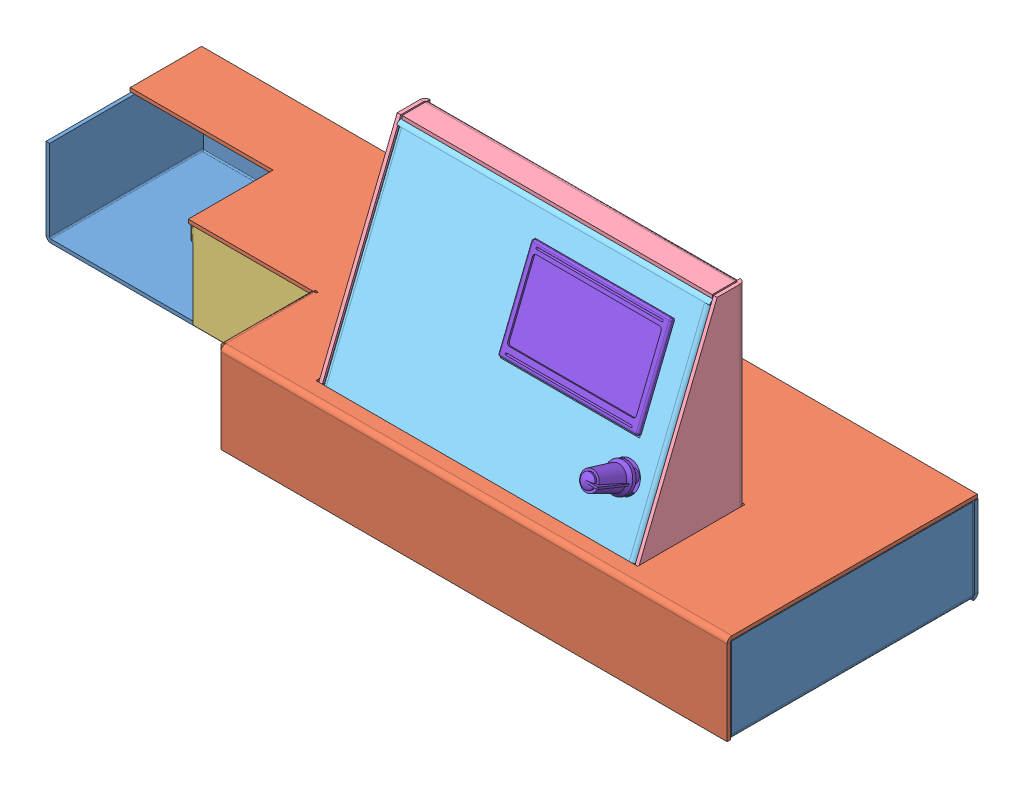
SolidWorks assembly case electronica, configuration Predeterminado. Lengths in mm.
Overall size (434 163.08 144.53).
15 component instances, 11 part files, 32 mates.
Components (placement in the parent):
- base case electronica-1: base case electronica [Predeterminado] at (-56.5036 -131.1225 434) size (434 48 138)
- Copia de Pieza2-1: Copia de Pieza2 [Predeterminado] at (0 0.5 0.4) size (434 50 140)
- Lateral case superior-1: Lateral case superior [Predeterminado] at (-0.5798 -10.8135 0.4) size (146 48 60)
- case panel base-1: case panel base [Predeterminado] at (10.9964 -29.5225 437.4) size (195 112.1 68)
- case panel frontal-1: case panel frontal [Predeterminado] at (10.9964 -30.4772 474.3319) x (1 0 0) z (0 0.374607 0.927184) size (175 123.88 18.04)
- bisagra conjunto-1: bisagra conjunto [Predeterminado] at (-193.3933 -102.5076 359.5703) size (40 28.4 28.4) (flexible)
  - bisagra 01-1: bisagra 01 [Predeterminado] at (-38.1103 2.1851 8.1797) size (40 28.4 3)
  - bisagra 02-1: bisagra 02 [Predeterminado] at (-38.1103 17.1351 23.1297) x (-1 0 0) z (0 -1 0) size (40 28.4 3)
- bisagra conjunto-2: bisagra conjunto [Predeterminado] at (156.6067 -102.5076 359.5703) size (40 28.4 28.4) (flexible)
  - bisagra 01-1: bisagra 01 [Predeterminado] at (-38.1103 2.1851 8.1797) size (40 28.4 3)
  - bisagra 02-1: bisagra 02 [Predeterminado] at (-38.1103 17.1351 23.1297) x (-1 0 0) z (0 -1 0) size (40 28.4 3)
- Display Controlador LCD Ramps 1.4-1: Display Controlador LCD Ramps 1.4 [Predeterminado] at (44.4964 -26.4399 459.5426) x (1 0 0) z (0 0.374607 0.927184) size (93 87.2 45.8)
- Arduino MEGA 2560 R3-1: Arduino MEGA 2560 R3 [Predeterminado] at (-34.9425 -75.8165 443.9) x (0 -1 0) z (-1 0 0) size (53.34 14.5 108.1)
- Shield Ramps 1.4-1: Shield Ramps 1.4 [Predeterminado] at (-35.3584 -79.6225 456.5471) x (0 -1 0) z (-1 0 0) size (61.76 37.63 106.38)
- Pieza6^case electronica-1: Pieza6^case electronica [Predeterminado] at (-43.3712 -108.7959 -211.9527) size (153.85 61.76 5) (virtual)
Mates (geometry in assembly coordinates):
- Coincidente1: coincident: plane of assembly; plane of assembly; plane of Copia de Pieza2-1 through (100.4964 -92.6225 495.4) normal (-1 0 0); plane of case panel base-1 through (100.4964 -29.5225 437.4) normal (1 0 0)
- Coincidente2: coincident: plane of assembly; plane of assembly; plane of Copia de Pieza2-1 through (-79.5036 -92.6225 435.4) normal (0 0 1); plane of case panel base-1 through (10.9964 -29.5225 435.4) normal (0 0 -1)
- Coincidente3: coincident: plane of assembly; plane of assembly; plane of Copia de Pieza2-1 through (0 -84.6225 0.4) normal (0 -1 0); plane of case panel base-1 through (10.9964 -84.6225 437.4) normal (0 1 0)
- Coincidente4: coincident: plane of assembly; plane of assembly; plane of case panel base-1 through (10.9964 23.4775 437.4) normal (0 -1 0); plane of case panel frontal-1 through (10.9964 23.4775 475.14) normal (0 1 0)
- Coincidente5: coincident: plane of assembly; plane of assembly; plane of case panel base-1 through (-76.5036 -29.5225 437.4) normal (1 0 0); plane of case panel frontal-1 through (-76.5036 -30.4772 474.3319) normal (-1 0 0)
- Coincidente6: coincident: line of assembly; plane of assembly; line of Copia de Pieza2-1 through (-79.5036 -82.6225 495.4) axis (1 0 0); plane of case panel frontal-1 through (10.9964 -30.4772 474.3319) normal (0 0.374607 0.927184)
- Coincidente11: coincident: plane of assembly; plane of assembly; plane of Copia de Pieza2-1 through (-273.5036 -82.6225 452.9) normal (0 0 1); plane of Lateral case superior-1 through (-0.5798 -10.8135 452.9) normal (0 0 1)
- Coincidente12: coincident: plane of assembly; plane of assembly; plane of Copia de Pieza2-1 through (0 -84.6225 0.4) normal (0 -1 0); plane of Lateral case superior-1 through (-125.5036 -84.6225 450.9) normal (0 1 0)
- Coincidente13: coincident: plane of assembly; plane of assembly; plane of Copia de Pieza2-1 through (-193.5036 -127.6225 405.4) normal (-1 0 0); plane of Lateral case superior-1 through (-193.5036 -10.8135 0.4) normal (-1 0 0)
- Coincidente14: coincident: plane of assembly; plane of assembly; plane of base case electronica-1 through (-56.5036 -131.1225 367) normal (0 0 1); plane of bisagra conjunto-1/bisagra 01-1 through (-251.5036 -113.0225 367) normal (0 0 -1)
- Distancia1: distance = 1 mm: line of assembly; plane of assembly; line of bisagra conjunto-1/bisagra 01-1 through (-251.5036 -86.1225 367) axis (1 0 0); plane of base case electronica-1 through (160.4964 -85.1225 365) normal (0 1 0)
- Distancia2: distance = 20 mm: plane of assembly; plane of assembly; plane of bisagra conjunto-1/bisagra 02-1 through (-251.5036 -86.1225 368.5) normal (-1 0 0); plane of base case electronica-1 through (-271.5036 -131.1225 434) normal (1 0 0)
- Coincidente16: coincident: plane of base case electronica-1 through (-56.5036 -131.1225 367) normal (0 0 1); plane of bisagra conjunto-2/bisagra 01-1 through (98.4964 -113.0225 367) normal (0 0 -1)
- Distancia3: distance = 1 mm: line of bisagra conjunto-2/bisagra 01-1 through (98.4964 -86.1225 367) axis (1 0 0); plane of base case electronica-1 through (160.4964 -85.1225 365) normal (0 1 0)
- Distancia4: distance = 20 mm: plane of bisagra conjunto-2/bisagra 01-1 through (138.4964 -86.1225 368.5) normal (1 0 0); plane of base case electronica-1 through (158.4964 -131.1225 434) normal (-1 0 0)
- Distancia5: distance = 30 mm: line of assembly; plane of assembly; line of Copia de Pieza2-1 through (160.4964 -84.6225 365.4) axis (-1 0 0); plane of bisagra conjunto-1/bisagra 02-1 through (-211.5036 -86.1225 395.4) normal (0 0 1)
- Coincidente18: coincident: plane of assembly; plane of assembly; plane of base case electronica-1 through (-273.5036 -131.1225 434) normal (-1 0 0); plane of Copia de Pieza2-1 through (-273.5036 -82.6225 452.9) normal (-1 0 0)
- Coincidente19: coincident: unknown of ?; unknown of ?
- Paralelo2: parallel: plane of Copia de Pieza2-1 through (0 -84.6225 0.4) normal (0 -1 0); plane of bisagra conjunto-2/bisagra 02-1 through (138.4964 -84.6225 395.4) normal (0 1 0)
- Ángulo límite1: limit planar angle = 0 rad: plane of assembly; plane of assembly; plane of Copia de Pieza2-1 through (0 -84.6225 0.4) normal (0 -1 0); plane of base case electronica-1 through (160.4964 -85.1225 503) normal (0 1 0)
- Coincidente20: coincident: plane of assembly; plane of assembly; plane of Copia de Pieza2-1 through (0 -84.6225 0.4) normal (0 -1 0); plane of bisagra conjunto-1/bisagra 02-1 through (-211.5036 -84.6225 395.4) normal (0 1 0)
- Coincidente21: coincident: unknown of ?; unknown of ?
- Coincidente24: coincident: plane of assembly; plane of assembly; plane of case panel frontal-1 through (83.4964 -25.6556 369.1203) normal (0 -0.927184 0.374607); plane of Display Controlador LCD Ramps 1.4-1 through (5.4964 10.9975 459.84) normal (0 0.927184 -0.374607)
- Coincidente25: coincident: plane of assembly; plane of assembly; plane of case panel frontal-1 through (5.4964 -25.6556 369.1203) normal (1 0 0); plane of Display Controlador LCD Ramps 1.4-1 through (5.4964 10.9975 459.84) normal (-1 0 0)
- Distancia7: distance = 1 mm: plane of assembly; plane of assembly; plane of Display Controlador LCD Ramps 1.4-1 through (44.4964 -22.9935 468.0727) normal (0 0.374607 0.927184); plane of case panel frontal-1 through (10.9964 -31.2264 472.4775) normal (0 -0.374607 -0.927184)
- Coincidente26: coincident: plane of assembly; plane of assembly; plane of Arduino MEGA 2560 R3-1 through (62.0855 -51.1785 446.6247) normal (-1 0 0); plane of Shield Ramps 1.4-1 through (62.0855 -51.8185 448.5407) normal (1 0 0)
- Coincidente27: coincident: plane of assembly; plane of assembly; plane of Arduino MEGA 2560 R3-1 through (62.0855 -51.1785 446.6247) normal (0 -1 0); plane of Shield Ramps 1.4-1 through (59.0655 -51.1785 459.4907) normal (0 1 0)
- Coincidente28: coincident: plane of assembly; plane of assembly; plane of Arduino MEGA 2560 R3-1 through (60.3075 -73.2765 453.9907) normal (0 0 1); plane of Shield Ramps 1.4-1 through (60.4955 -48.7089 453.9907) normal (0 0 -1)
- Bloquear1: lock: unknown of Arduino MEGA 2560 R3-1; unknown of Pieza6^case electronica-1
- Coincidente30: coincident: plane of assembly; plane of assembly; plane of case panel base-1 through (10.9964 -29.5225 437.4) normal (0 0 1); plane of Pieza6^case electronica-1 through (-43.3712 -108.7959 437.4) normal (0 0 -1)
- Distancia8: distance = 5 mm: plane of assembly; plane of assembly; plane of Pieza6^case electronica-1 through (93.4964 -89.6225 437.4) normal (0 -1 0); plane of Copia de Pieza2-1 through (0 -84.6225 0.4) normal (0 -1 0)
- Distancia10: distance = 5 mm: line of assembly; plane of assembly; line of Pieza6^case electronica-1 through (93.4964 -84.6225 442.4) axis (0 0 -1); plane of case panel base-1 through (98.4964 -29.5225 437.4) normal (-1 0 0)
